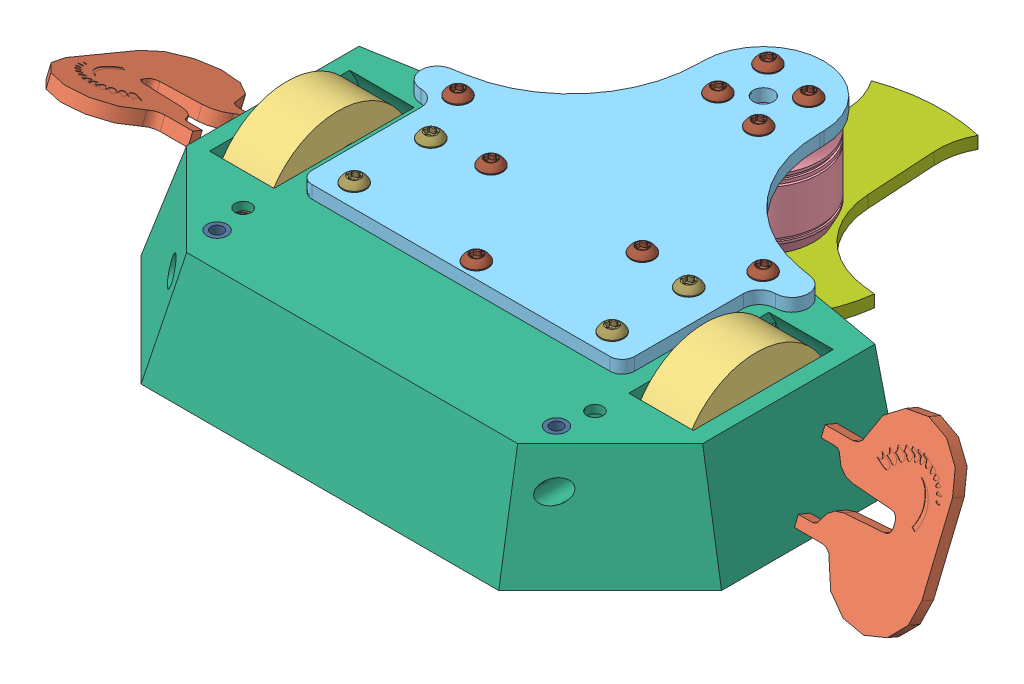
SolidWorks assembly Detcord-Mini, configuration Default. Lengths in mm.
Overall size (144 44.17 156.21).
50 component instances, 18 part files, 66 mates.
Components (placement in the parent):
- drive-motor-repeatant-1: drive-motor-repeatant [Default] at (-40 19.05 0) x (0 0 -1) z (1 0 0) size (16 16 54.1)
- wheel-hub-fttwist-1: wheel-hub-fttwist [Default] at (-44 19.05 0) x (0 0.924225 0.381849) z (-1 0 0) size (32.09 32.09 60.58)
- wheel-foam-ft1p5in-1: wheel-foam-ft1p5in [Default] at (-58.224 19.05 0) size (12.7 38.1 38.1)
- bldc-motor-repeatdirect2822-1: bldc-motor-repeatdirect2822 [Default] at (0 30.925 -60) x (-0.837169 0 -0.546944) z (-0.546944 0 0.837169) size (28 37 28)
- chassis-plate^Detcord-Mini-1: chassis-plate^Detcord-Mini [Default] at origin size (96.11 3.17 90) (virtual)
- chassis-body^Detcord-Mini-1: chassis-body^Detcord-Mini [Default] at origin size (144 25.93 78.69) (virtual)
- blade-1: blade [Default] at (0 5.925 -60) x (0.998214 0 -0.059736) z (0.059736 0 0.998214) size (61.75 3 75.8)
- lid^Detcord-Mini-1: lid^Detcord-Mini [Default] at origin size (128 1 87) (virtual)
- motor-clamp^Detcord-Mini-1: motor-clamp^Detcord-Mini [Default] at origin size (16 12.25 30) (virtual)
- standoff-m3-25mm-1: standoff-m3-25mm [Default] at (-37.8485 5.925 -22.1072) size (5 25 5)
- standoff-m3-25mm-2: standoff-m3-25mm [Default] at (-18.7799 5.925 -11.2201) size (5 25 5)
- standoff-m3-25mm-3: standoff-m3-25mm [Default] at (37.8485 5.925 -22.1072) size (5 25 5)
- standoff-m3-25mm-4: standoff-m3-25mm [Default] at (18.7799 5.925 -11.2201) size (5 25 5)
- standoff-m3-25mm-5: standoff-m3-25mm [Default] at (-42.1005 5.925 33.414) size (5 25 5)
- standoff-m3-25mm-6: standoff-m3-25mm [Default] at (42.1005 5.925 33.414) size (5 25 5)
- screw-m3-8mm-90991A113-1: screw-m3-8mm-90991A113 [90991A113] at (-6.1193 30.925 -67.2667) x (1 0 0) z (0 1 0) size (5.7 5.7 9.89)
- screw-m3-8mm-90991A113-2: screw-m3-8mm-90991A113 [90991A113] at (6.1193 30.925 -65.1531) x (1 0 0) z (0 1 0) size (5.7 5.7 9.89)
- screw-m3-8mm-90991A113-4: screw-m3-8mm-90991A113 [90991A113] at (-6.1193 30.925 -54.8469) x (1 0 0) z (0 1 0) size (5.7 5.7 9.89)
- screw-m3-8mm-90991A113-5: screw-m3-8mm-90991A113 [90991A113] at (-18.7799 7.175 -11.2201) x (1 0 0) z (0 -1 0) size (5.7 5.7 9.89)
- screw-m3-8mm-90991A113-6: screw-m3-8mm-90991A113 [90991A113] at (-37.8485 30.925 -22.1072) x (1 0 0) z (0 1 0) size (5.7 5.7 9.89)
- screw-m3-8mm-90991A113-7: screw-m3-8mm-90991A113 [90991A113] at (0 30.925 11.2) x (1 0 0) z (0 1 0) size (5.7 5.7 9.89)
- screw-m3-8mm-90991A113-10: screw-m3-8mm-90991A113 [90991A113] at (-37.8485 7.175 -22.1072) x (1 0 0) z (0 -1 0) size (5.7 5.7 9.89)
- screw-m3-8mm-90991A113-11: screw-m3-8mm-90991A113 [90991A113] at (-18.7799 30.925 -11.2201) x (1 0 0) z (0 1 0) size (5.7 5.7 9.89)
- screw-m3-8mm-90991A113-13: screw-m3-8mm-90991A113 [90991A113] at (6.1193 30.925 -52.7333) x (1 0 0) z (0 1 0) size (5.7 5.7 9.89)
- screw-m3-8mm-90991A113-14: screw-m3-8mm-90991A113 [90991A113] at (-42.1005 7.175 33.414) x (1 0 0) z (0 -1 0) size (5.7 5.7 9.89)
- screw-m3-30mm-92832A567-1: screw-m3-30mm-92832A567 [92832A567] at (-32 19.1 9.5) x (1 0 0) z (0 1 0) size (5.7 5.7 31.97)
- screw-m3-30mm-92832A567-2: screw-m3-30mm-92832A567 [92832A567] at (-32 19.1 -9.5) x (1 0 0) z (0 1 0) size (5.7 5.7 31.97)
- screw-m3-8mm-sockhead-91274A103-1: screw-m3-8mm-sockhead-91274A103 [91274A103] at (-9.983 8.425 -59.4167) x (1 0 0) z (0 -1 0) size (5.5 5.5 11.11)
- screw-m3-8mm-sockhead-91274A103-2: screw-m3-8mm-sockhead-91274A103 [91274A103] at (0.5965 8.425 -50.0319) x (1 0 0) z (0 -1 0) size (5.5 5.5 11.11)
- screw-m3-8mm-sockhead-91274A103-3: screw-m3-8mm-sockhead-91274A103 [91274A103] at (9.9813 8.425 -60.6114) x (1 0 0) z (0 -1 0) size (5.5 5.5 11.11)
- screw-m3-8mm-sockhead-91274A103-4: screw-m3-8mm-sockhead-91274A103 [91274A103] at (-0.5982 8.425 -69.9962) x (1 0 0) z (0 -1 0) size (5.5 5.5 11.11)
- motor-clamp^Detcord-Mini-2: motor-clamp^Detcord-Mini [Default] x (-1 0 0) z (0 0 -1) size (16 12.25 30) (virtual)
- wheel-foam-ft1p5in-2: wheel-foam-ft1p5in [Default] at (58.224 19.05 0) x (-1 0 0) z (0 0 -1) size (12.7 38.1 38.1)
- wheel-hub-fttwist-2: wheel-hub-fttwist [Default] at (44 19.05 0) x (0 0.924225 0.381849) z (1 0 0) size (32.09 32.09 60.58)
- drive-motor-repeatant-2: drive-motor-repeatant [Default] at (40 19.05 0) x (0 0 1) z (-1 0 0) size (16 16 54.1)
- screw-m3-8mm-90991A113-16: screw-m3-8mm-90991A113 [90991A113] at (18.7799 7.175 -11.2201) x (-1 0 0) z (0 -1 0) size (5.7 5.7 9.89)
- screw-m3-8mm-90991A113-17: screw-m3-8mm-90991A113 [90991A113] at (37.8485 30.925 -22.1072) x (-1 0 0) z (0 1 0) size (5.7 5.7 9.89)
- screw-m3-8mm-90991A113-18: screw-m3-8mm-90991A113 [90991A113] at (37.8485 7.175 -22.1072) x (-1 0 0) z (0 -1 0) size (5.7 5.7 9.89)
- screw-m3-8mm-90991A113-19: screw-m3-8mm-90991A113 [90991A113] at (18.7799 30.925 -11.2201) x (-1 0 0) z (0 1 0) size (5.7 5.7 9.89)
- screw-m3-8mm-90991A113-20: screw-m3-8mm-90991A113 [90991A113] at (42.1005 7.175 33.414) x (-1 0 0) z (0 -1 0) size (5.7 5.7 9.89)
- screw-m3-30mm-92832A567-5: screw-m3-30mm-92832A567 [92832A567] at (32 19.1 9.5) x (-1 0 0) z (0 1 0) size (5.7 5.7 31.97)
- screw-m3-30mm-92832A567-6: screw-m3-30mm-92832A567 [92832A567] at (32 19.1 -9.5) x (-1 0 0) z (0 1 0) size (5.7 5.7 31.97)
- dual-esc-1: dual-esc [Default] at (1.152 14.8 6) x (1 0 0) z (0 -1 0) size (24 5 18)
- batt-3s-660mah-65x24x18-1: batt-3s-660mah-65x24x18 [Default] at (-28.3406 16.925 31) x (1 0 0) z (0 -1 0) size (65 18 24)
- ft-pwr-switch-1: ft-pwr-switch [Default] at (-43.636 22.425 25.739) x (0 0 1) z (1 0 0) size (6.35 12.88 19.05)
  - Copy of PART A^ft-pwr-switch-1: Copy of PART A^ft-pwr-switch [Default] at origin size (3.18 12.7 12.7) (virtual)
  - Copy of PART A^ft-pwr-switch-2: Copy of PART A^ft-pwr-switch [Default] x (-1 0 0) z (0 0 -1) size (3.18 12.7 12.7) (virtual)
  - Copy of socket head cap screw_ai_HX-SHCS 0.086-56x0.375x0.375-S^ft-pwr-switch-1: Copy of socket head cap screw_ai_HX-SHCS 0.086-56x0.375x0.375-S^ft-pwr-switch [Default] at (0 -6.5344 0) x (0 1 0) z (0 0 1) size (11.71 3.56 3.56) (virtual)
  - Copy of TERMINAL^ft-pwr-switch-1: Copy of TERMINAL^ft-pwr-switch [Default] at (0 2 3.7) x (0 0 -1) z (0 1 0) size (18 3.5 1) (virtual)
  - Copy of TERMINAL^ft-pwr-switch-2: Copy of TERMINAL^ft-pwr-switch [Default] at (0 -3 3.7) x (0 0 -1) z (0 1 0) size (18 3.5 1) (virtual)
Mates (geometry in assembly coordinates):
- Coincident1: coincident aligned: line of drive-motor-repeatant-1 through (36.9268 -71.8 19.05) axis (0 1 0)
- Coincident2: coincident: plane of drive-motor-repeatant-1 through (-40 19.05 0) normal (-1 0 0)
- Coincident3: coincident aligned: line of wheel-hub-fttwist-1 through (14.33 -58.33 19.05) axis (0 1 0)
- Coincident4: coincident anti-aligned: plane of drive-motor-repeatant-1 through (-44 19.05 0) normal (-1 0 0); plane of wheel-hub-fttwist-1 through (-44 19.05 0) normal (1 0 0)
- Concentric1: concentric anti-aligned: cylinder of wheel-foam-ft1p5in-1 through (-45.524 19.05 0) axis (-1 0 0) radius 5
- Coincident5: coincident aligned: plane of wheel-hub-fttwist-1 through (-45.524 19.05 0) normal (1 0 0); plane of wheel-foam-ft1p5in-1 through (-45.524 19.05 0) normal (1 0 0)
- Parallel1: parallel aligned: plane of drive-motor-repeatant-1 through (-6.048 24.1516 6) normal (0 0 1)
- Concentric2: concentric anti-aligned: cylinder of bldc-motor-repeatdirect2822-1 through (0 -6.075 -60) axis (0 -1 0) radius 2
- Coincident7: coincident: plane of bldc-motor-repeatdirect2822-1 through (0 30.925 -60) normal (0 1 0)
- Coincident8: coordinate: unknown of chassis-plate^Detcord-Mini-1
- Coincident9: coordinate: unknown of chassis-body^Detcord-Mini-1
- Coincident10: coincident aligned: line of blade-1 through (0 -49.075 -60) axis (0 1 0)
- Coincident11: coincident: plane of blade-1 through (0 8.925 -60) normal (0 1 0)
- Coincident12: coordinate: unknown of lid^Detcord-Mini-1
- Coincident13: coordinate: unknown of motor-clamp^Detcord-Mini-1
- Coincident14: coincident aligned: plane of chassis-body^Detcord-Mini-1 through (0 30.925 -60) normal (0 1 0); plane of standoff-m3-25mm-1 through (-37.8485 30.925 -22.1072) normal (0 1 0)
- Concentric3: concentric aligned: cylinder of chassis-body^Detcord-Mini-1 through (-37.8485 30.925 -22.1072) axis (0 -1 0) radius 2.5; cylinder of standoff-m3-25mm-1 through (-37.8485 30.925 -22.1072) axis (0 -1 0) radius 2.5
- Coincident15: coincident aligned: plane of chassis-body^Detcord-Mini-1 through (0 30.925 -60) normal (0 1 0); plane of standoff-m3-25mm-2 through (-18.7799 30.925 -11.2201) normal (0 1 0)
- Concentric4: concentric aligned: cylinder of chassis-body^Detcord-Mini-1 through (-18.7799 30.925 -11.2201) axis (0 -1 0) radius 2.5; cylinder of standoff-m3-25mm-2 through (-18.7799 30.925 -11.2201) axis (0 -1 0) radius 2.5
- Concentric5: concentric aligned: cylinder of chassis-body^Detcord-Mini-1 through (-42.1005 30.925 33.414) axis (0 -1 0) radius 2.5; cylinder of standoff-m3-25mm-5 through (-42.1005 30.925 33.414) axis (0 -1 0) radius 2.5
- Coincident16: coincident aligned: plane of chassis-body^Detcord-Mini-1 through (0 30.925 -60) normal (0 1 0); plane of standoff-m3-25mm-5 through (-42.1005 30.925 33.414) normal (0 1 0)
- Concentric6: concentric aligned: cylinder of chassis-body^Detcord-Mini-1 through (18.7799 30.925 -11.2201) axis (0 -1 0) radius 2.5; cylinder of standoff-m3-25mm-4 through (18.7799 30.925 -11.2201) axis (0 -1 0) radius 2.5
- Coincident17: coincident aligned: plane of chassis-body^Detcord-Mini-1 through (0 30.925 -60) normal (0 1 0); plane of standoff-m3-25mm-4 through (18.7799 30.925 -11.2201) normal (0 1 0)
- Concentric7: concentric aligned: cylinder of chassis-body^Detcord-Mini-1 through (37.8485 30.925 -22.1072) axis (0 -1 0) radius 2.5; cylinder of standoff-m3-25mm-3 through (37.8485 30.925 -22.1072) axis (0 -1 0) radius 2.5
- Coincident18: coincident aligned: plane of chassis-body^Detcord-Mini-1 through (0 30.925 -60) normal (0 1 0); plane of standoff-m3-25mm-3 through (37.8485 30.925 -22.1072) normal (0 1 0)
- Concentric8: concentric aligned: cylinder of chassis-body^Detcord-Mini-1 through (42.1005 30.925 33.414) axis (0 -1 0) radius 2.5; cylinder of standoff-m3-25mm-6 through (42.1005 30.925 33.414) axis (0 -1 0) radius 2.5
- Coincident19: coincident aligned: plane of chassis-body^Detcord-Mini-1 through (0 30.925 -60) normal (0 1 0); plane of standoff-m3-25mm-6 through (42.1005 30.925 33.414) normal (0 1 0)
- Coincident20: coincident anti-aligned: plane of chassis-plate^Detcord-Mini-1 through (46.7753 34.1 -59) normal (0 1 0); plane of screw-m3-30mm-92832A567-1 through (-32 34.1 12.35) normal (0 -1 0)
- Concentric9: concentric aligned: cylinder of chassis-plate^Detcord-Mini-1 through (-32 30.925 9.5) axis (0 1 0) radius 1.5; cylinder of screw-m3-30mm-92832A567-1 through (-32 35.75 9.5) axis (0 1 0) radius 2.85
- Coincident21: coincident anti-aligned: plane of chassis-plate^Detcord-Mini-1 through (46.7753 34.1 -59) normal (0 1 0); plane of screw-m3-30mm-92832A567-2 through (-32 34.1 -6.65) normal (0 -1 0)
- Concentric10: concentric aligned: cylinder of chassis-plate^Detcord-Mini-1 through (-32 30.925 -9.5) axis (0 1 0) radius 1.5; cylinder of screw-m3-30mm-92832A567-2 through (-32 35.75 -9.5) axis (0 1 0) radius 2.85
- Coincident22: coincident anti-aligned: plane of chassis-plate^Detcord-Mini-1 through (46.7753 34.1 -59) normal (0 1 0); plane of screw-m3-8mm-90991A113-6 through (-37.8485 34.1 -24.9572) normal (0 -1 0)
- Concentric11: concentric anti-aligned: cylinder of chassis-plate^Detcord-Mini-1 through (-37.8485 30.925 -22.1072) axis (0 1 0) radius 1.5; cylinder of screw-m3-8mm-90991A113-6 through (-37.8485 26.1 -22.1072) axis (0 -1 0) radius 2.85
- Coincident23: coincident anti-aligned: plane of chassis-plate^Detcord-Mini-1 through (46.7753 34.1 -59) normal (0 1 0); plane of screw-m3-8mm-90991A113-11 through (-18.7799 34.1 -14.0701) normal (0 -1 0)
- Concentric12: concentric anti-aligned: cylinder of chassis-plate^Detcord-Mini-1 through (-18.7799 30.925 -11.2201) axis (0 1 0) radius 1.5; cylinder of screw-m3-8mm-90991A113-11 through (-18.7799 26.1 -11.2201) axis (0 -1 0) radius 2.85
- Coincident24: coincident anti-aligned: plane of chassis-plate^Detcord-Mini-1 through (46.7753 34.1 -59) normal (0 1 0); plane of screw-m3-8mm-90991A113-7 through (0 34.1 8.35) normal (0 -1 0)
- Concentric13: concentric anti-aligned: cylinder of chassis-plate^Detcord-Mini-1 through (0 30.925 11.2) axis (0 1 0) radius 1.5; cylinder of screw-m3-8mm-90991A113-7 through (0 26.1 11.2) axis (0 -1 0) radius 2.85
- Coincident25: coincident anti-aligned: plane of lid^Detcord-Mini-1 through (0 4 -60) normal (0 -1 0); plane of screw-m3-8mm-90991A113-10 through (-37.8485 4 -19.2572) normal (0 1 0)
- Concentric14: concentric aligned: cylinder of lid^Detcord-Mini-1 through (-37.8485 4 -22.1072) axis (0 1 0) radius 1.5; cylinder of screw-m3-8mm-90991A113-10 through (-37.8485 12 -22.1072) axis (0 1 0) radius 2.85
- Coincident26: coincident anti-aligned: plane of lid^Detcord-Mini-1 through (0 4 -60) normal (0 -1 0); plane of screw-m3-8mm-90991A113-5 through (-18.7799 4 -8.3701) normal (0 1 0)
- Concentric15: concentric aligned: cylinder of lid^Detcord-Mini-1 through (-18.7799 4 -11.2201) axis (0 1 0) radius 1.5; cylinder of screw-m3-8mm-90991A113-5 through (-18.7799 12 -11.2201) axis (0 1 0) radius 2.85
- Coincident27: coincident anti-aligned: plane of chassis-plate^Detcord-Mini-1 through (46.7753 34.1 -59) normal (0 1 0); plane of screw-m3-8mm-90991A113-4 through (-6.1193 34.1 -57.6969) normal (0 -1 0)
- Concentric16: concentric anti-aligned: cylinder of chassis-plate^Detcord-Mini-1 through (-6.1193 30.925 -54.8469) axis (0 1 0) radius 1.5; cylinder of screw-m3-8mm-90991A113-4 through (-6.1193 26.1 -54.8469) axis (0 -1 0) radius 2.85
- Coincident28: coincident anti-aligned: plane of chassis-plate^Detcord-Mini-1 through (46.7753 34.1 -59) normal (0 1 0); plane of screw-m3-8mm-90991A113-13 through (6.1193 34.1 -55.5833) normal (0 -1 0)
- Concentric17: concentric anti-aligned: cylinder of chassis-plate^Detcord-Mini-1 through (6.1193 30.925 -52.7333) axis (0 1 0) radius 1.5; cylinder of screw-m3-8mm-90991A113-13 through (6.1193 26.1 -52.7333) axis (0 -1 0) radius 2.85
- Coincident29: coincident anti-aligned: plane of chassis-plate^Detcord-Mini-1 through (46.7753 34.1 -59) normal (0 1 0); plane of screw-m3-8mm-90991A113-2 through (6.1193 34.1 -68.0031) normal (0 -1 0)
- Concentric18: concentric anti-aligned: cylinder of chassis-plate^Detcord-Mini-1 through (6.1193 30.925 -65.1531) axis (0 1 0) radius 1.5; cylinder of screw-m3-8mm-90991A113-2 through (6.1193 26.1 -65.1531) axis (0 -1 0) radius 2.85
- Coincident30: coincident anti-aligned: plane of chassis-plate^Detcord-Mini-1 through (46.7753 34.1 -59) normal (0 1 0); plane of screw-m3-8mm-90991A113-1 through (-6.1193 34.1 -70.1167) normal (0 -1 0)
- Concentric19: concentric anti-aligned: cylinder of chassis-plate^Detcord-Mini-1 through (-6.1193 30.925 -67.2667) axis (0 1 0) radius 1.5; cylinder of screw-m3-8mm-90991A113-1 through (-6.1193 26.1 -67.2667) axis (0 -1 0) radius 2.85
- Coincident31: coincident anti-aligned: plane of lid^Detcord-Mini-1 through (0 4 -60) normal (0 -1 0); plane of screw-m3-8mm-90991A113-14 through (-42.1005 4 36.264) normal (0 1 0)
- Concentric20: concentric aligned: cylinder of lid^Detcord-Mini-1 through (-42.1005 4 33.414) axis (0 1 0) radius 1.5; cylinder of screw-m3-8mm-90991A113-14 through (-42.1005 12 33.414) axis (0 1 0) radius 2.85
- Coincident32: coincident anti-aligned: plane of blade-1 through (0 5.925 -60) normal (0 -1 0); plane of screw-m3-8mm-sockhead-91274A103-4 through (-0.5982 5.925 -68.4962) normal (0 1 0)
- Coincident33: coincident anti-aligned: plane of blade-1 through (0 5.925 -60) normal (0 -1 0); plane of screw-m3-8mm-sockhead-91274A103-3 through (9.9813 5.925 -59.1114) normal (0 1 0)
- Coincident34: coincident anti-aligned: plane of blade-1 through (0 5.925 -60) normal (0 -1 0); plane of screw-m3-8mm-sockhead-91274A103-2 through (0.5965 5.925 -48.5319) normal (0 1 0)
- Coincident35: coincident anti-aligned: plane of blade-1 through (0 5.925 -60) normal (0 -1 0); plane of screw-m3-8mm-sockhead-91274A103-1 through (-9.983 5.925 -57.9167) normal (0 1 0)
- Concentric21: concentric anti-aligned: cylinder of blade-1 through (-9.983 5.925 -59.4167) axis (0 1 0) radius 1.5; cylinder of screw-m3-8mm-sockhead-91274A103-1 through (-9.983 2.925 -59.4167) axis (0 -1 0) radius 2.7285
- Concentric22: concentric anti-aligned: cylinder of blade-1 through (0.5965 5.925 -50.0319) axis (0 1 0) radius 1.5; cylinder of screw-m3-8mm-sockhead-91274A103-2 through (0.5965 2.925 -50.0319) axis (0 -1 0) radius 2.7285
- Concentric23: concentric anti-aligned: cylinder of blade-1 through (9.9813 5.925 -60.6114) axis (0 1 0) radius 1.5; cylinder of screw-m3-8mm-sockhead-91274A103-3 through (9.9813 2.925 -60.6114) axis (0 -1 0) radius 2.7285
- Concentric24: concentric anti-aligned: cylinder of blade-1 through (-0.5982 5.925 -69.9962) axis (0 1 0) radius 1.5; cylinder of screw-m3-8mm-sockhead-91274A103-4 through (-0.5982 2.925 -69.9962) axis (0 -1 0) radius 2.7285
- Coincident37: coincident aligned: plane of motor-clamp^Detcord-Mini-1 through (0 5.8 0) normal (0 -1 0); plane of dual-esc-1 through (-10.848 5.8 11) normal (0 -1 0)
- Coincident38: coincident anti-aligned: plane of drive-motor-repeatant-1 through (-6.048 24.1516 6) normal (0 0 1); plane of dual-esc-1 through (1.152 14.8 6) normal (0 0 -1)
- Coincident40: coincident anti-aligned: plane of chassis-body^Detcord-Mini-1 through (0 28.925 -60) normal (0 -1 0); plane of batt-3s-660mah-65x24x18-1 through (36.6594 28.925 22) normal (0 1 0)
- Coincident41: coincident anti-aligned: plane of chassis-body^Detcord-Mini-1 through (-39.05 19.05 40) normal (0 0 -1); plane of batt-3s-660mah-65x24x18-1 through (36.6594 4.925 40) normal (0 0 1)
- Coincident43: coincident anti-aligned: plane of chassis-body^Detcord-Mini-1 through (-42.1005 15.925 28.914) normal (0 0 -1); plane of ft-pwr-switch-1/Copy of PART A^ft-pwr-switch-1 through (-43.636 22.425 28.914) normal (0 0 1)
- Concentric26: concentric anti-aligned: cylinder of chassis-body^Detcord-Mini-1 through (-47.446 22.425 50) axis (0 0 -1) radius 1; cylinder of ft-pwr-switch-1/Copy of PART A^ft-pwr-switch-2 through (-47.446 22.425 25.739) axis (0 0 1) radius 0.889
- Parallel3: parallel aligned: plane of chassis-body^Detcord-Mini-1 through (0 28.925 -60) normal (0 -1 0); plane of ft-pwr-switch-1/Copy of PART A^ft-pwr-switch-2 through (-49.986 16.075 22.564) normal (0 -1 0)
